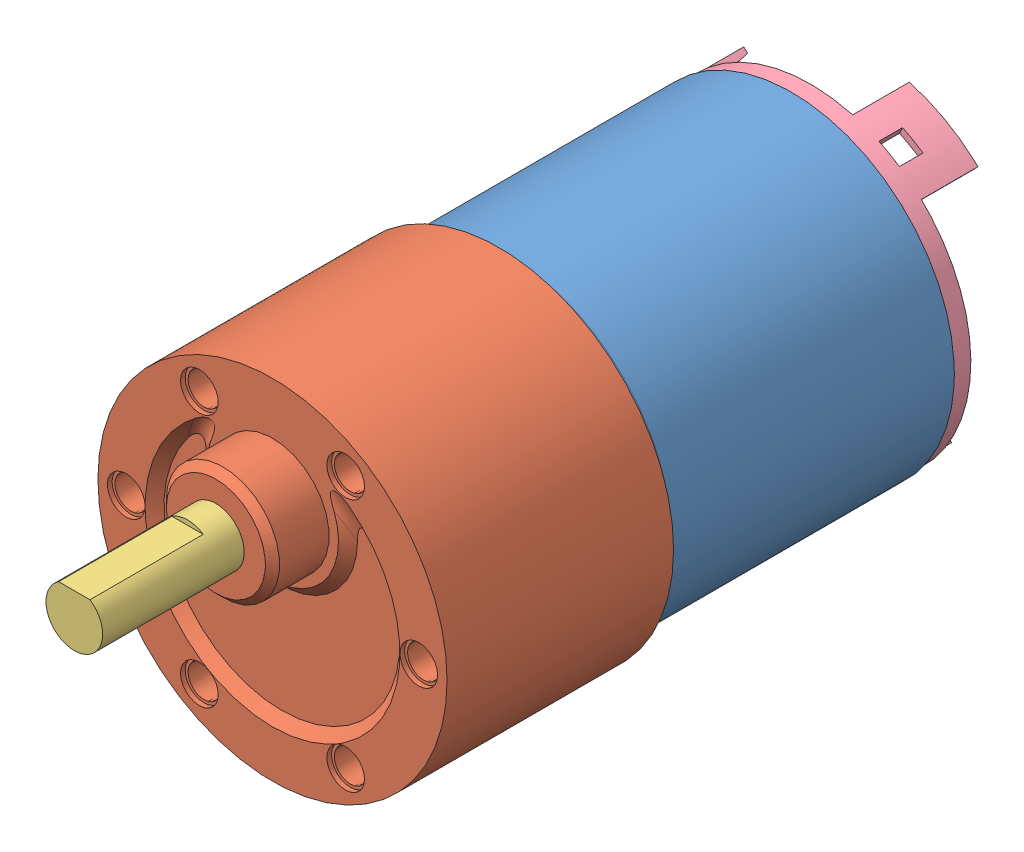
SolidWorks assembly Motor_ASM_rev0, configuration Default. Lengths in mm.
Overall size (42.65 42.65 84).
4 component instances, 4 part files, 7 mates.
Components (placement in the parent):
- Motor_rev0-1: Motor_rev0 [Default] at (12.0471 18.5029 10.1025) size (34.5 34.5 31)
- Gearbox_rev0-1: Gearbox_rev0 [Default] at (12.0471 18.5029 41.1025) size (37 37 30)
- Shaft_rev0-1: Shaft_rev0 [Default] at (12.0471 25.5029 65.1025) size (6 6 21)
- Back_Motor_Cover_rev0-1: Back_Motor_Cover_rev0 [Default] at (12.0471 18.5029 10.1025) x (0.953717 0.300706 0) z (0 0 -1) size (34 34 8)
Mates (geometry in assembly coordinates):
- Coincident1: coincident anti-aligned: plane of Motor_rev0-1 through (12.0471 18.5029 41.1025) normal (0 0 1); plane of Gearbox_rev0-1 through (12.0471 18.5029 41.1025) normal (0 0 -1)
- Concentric1: concentric aligned: cylinder of Motor_rev0-1 through (12.0471 18.5029 41.1025) axis (0 0 -1) radius 17.25; cylinder of Gearbox_rev0-1 through (12.0471 18.5029 65.1025) axis (0 0 -1) radius 18.5
- Lock1: lock: unknown of Motor_rev0-1; unknown of Gearbox_rev0-1
- Hinge1: hinge anti-aligned: cylinder of Gearbox_rev0-1 through (12.0471 25.5029 71.1025) axis (0 0 -1) radius 3; cylinder of Gearbox_rev0-1 through (12.0471 25.5029 86.1025) axis (0 0 -1) radius 3; plane of Shaft_rev0-1 through (12.0471 18.5029 65.1025) normal (0 0 1); plane of Shaft_rev0-1 through (12.0471 25.5029 65.1025) normal (0 0 -1)
- Coincident2: coincident anti-aligned: plane of Motor_rev0-1 through (12.0471 18.5029 10.1025) normal (0 0 -1); plane of Back_Motor_Cover_rev0-1 through (12.0471 18.5029 10.1025) normal (0 0 1)
- Concentric2: concentric anti-aligned: cylinder of Motor_rev0-1 through (12.0471 18.5029 41.1025) axis (0 0 -1) radius 17.25; cylinder of Back_Motor_Cover_rev0-1 through (12.0471 18.5029 8.1025) axis (0 0 1) radius 17
- Coincident3: coincident aligned: plane of Shaft_rev0-1 through (12.0471 25.5029 65.1025) normal (1 0 0); plane of Back_Motor_Cover_rev0-1 through (12.0471 18.5029 10.1025) normal (1 0 0)
